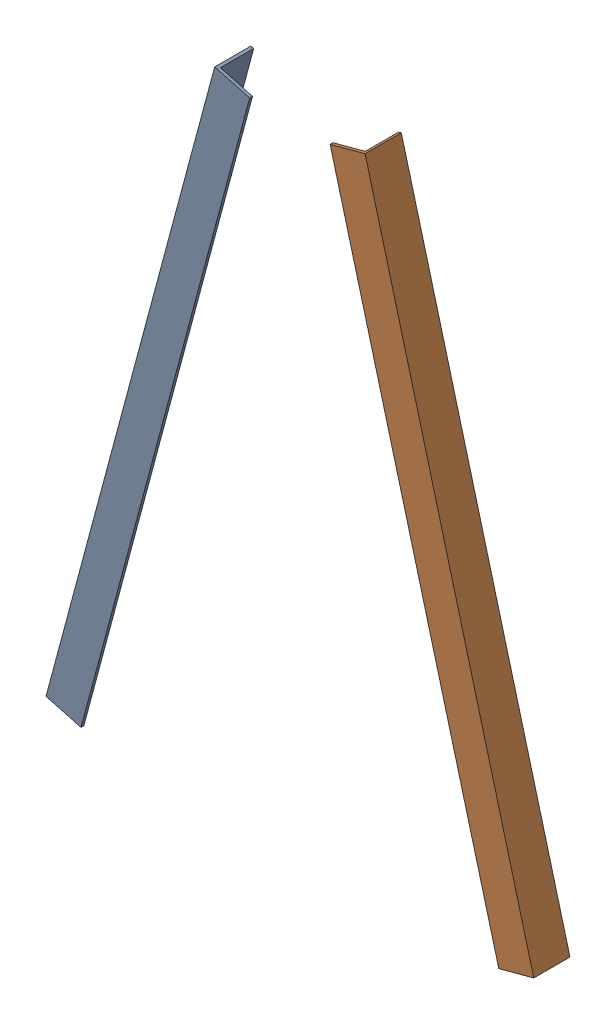
SolidWorks assembly Сборка2, configuration По умолчанию. Lengths in mm.
Overall size (673.6 882.27 50).
2 component instances, 1 part files, 7 mates.
Components (placement in the parent):
- Уголок150КОЗ-1: Уголок150КОЗ [По умолчанию] at (0.1363 1.0353 0) x (0.965926 -0.258819 0) z (0 0 1) size (50 900 50)
- Уголок150КОЗ-2: Уголок150КОЗ [По умолчанию] at (673.738 1.0353 0) x (0 0 -1) z (0.965926 0.258819 0) size (50 900 50)
Mates (geometry in assembly coordinates):
- Совпадение1: coincident: line of Уголок150КОЗ-1 through (4 0 -50) axis (0 0 1)
- Совпадение2: coincident aligned: plane of Уголок150КОЗ-1 through (233.0734 870.3685 0) normal (0 0 1)
- Угол1: planar angle = 0.261799 rad aligned: plane of Уголок150КОЗ-1 through (236.9371 869.3332 -50) normal (0.965926 -0.258819 0)
- Совпадение4: coincident: line of Уголок150КОЗ-2 through (619.8743 0 -4) axis (0 0 -1)
- Совпадение5: coincident aligned: plane of Уголок150КОЗ-1 through (233.0734 870.3685 0) normal (0 0 1); plane of Уголок150КОЗ-2 through (342.5046 857.4276 0) normal (0 0 1)
- Угол2: planar angle = 0.523599 rad anti-aligned: plane of Уголок150КОЗ-2 through (436.9371 869.3332 0) normal (-0.965926 -0.258819 0); plane of Уголок150КОЗ-1 through (236.9371 869.3332 -50) normal (0.965926 -0.258819 0)
- Расстояние2: distance = 200 mm: line of Уголок150КОЗ-1 through (236.9371 869.3332 -50) axis (0 0 1); line of Уголок150КОЗ-2 through (436.9371 869.3332 -4) axis (0 0 -1)
